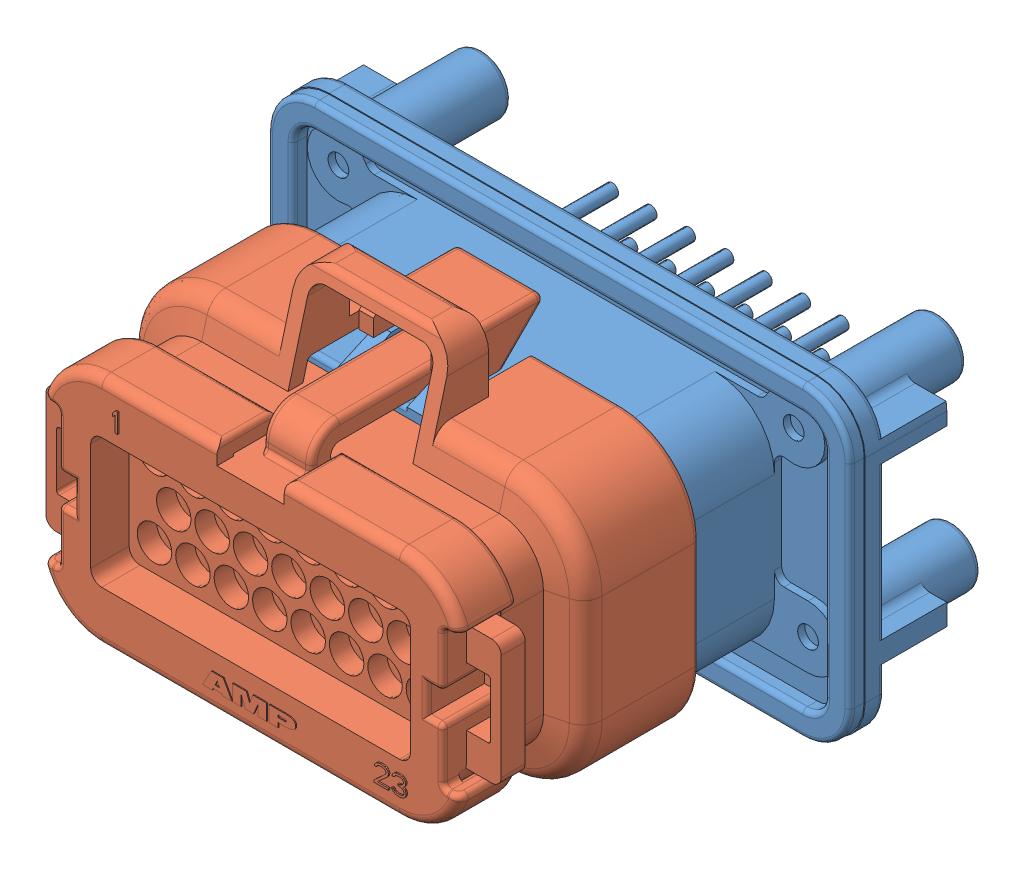
SolidWorks assembly c-776228-1_ASM, configuration Default. Lengths in mm.
Overall size (60.8 36.85 51.83).
2 component instances, 2 part files, 3 mates.
Components (placement in the parent):
- c-1-776228-1-e-3d-1: c-1-776228-1-e-3d [Default] at (-11.8296 11.6312 17.3771) size (60.8 32.1 38.08)
- c-770680-1-l-3d-1: c-770680-1-l-3d [Default] at (-11.8296 11.6312 7.9771) x (-1 0 0) z (0 0 -1) size (47.4 34.6 33.75)
Mates (geometry in assembly coordinates):
- Concentric1: concentric anti-aligned: cylinder of c-1-776228-1-e-3d-1 through (-25.8296 7.6312 -2.6229) axis (0 0 1) radius 0.65; cylinder of c-770680-1-l-3d-1 through (-25.8296 7.6312 -2.6229) axis (0 0 -1) radius 0.9
- Parallel1: parallel anti-aligned: plane of c-1-776228-1-e-3d-1 through (3.6704 21.9312 17.3771) normal (0 -1 0); plane of c-770680-1-l-3d-1 through (3.6204 20.0812 13.8771) normal (0 1 0)
- Coincident2: coincident anti-aligned: plane of c-1-776228-1-e-3d-1 through (-11.8296 11.6312 -2.6229) normal (0 0 1); plane of c-770680-1-l-3d-1 through (-11.8296 11.6312 -2.6229) normal (0 0 -1)
